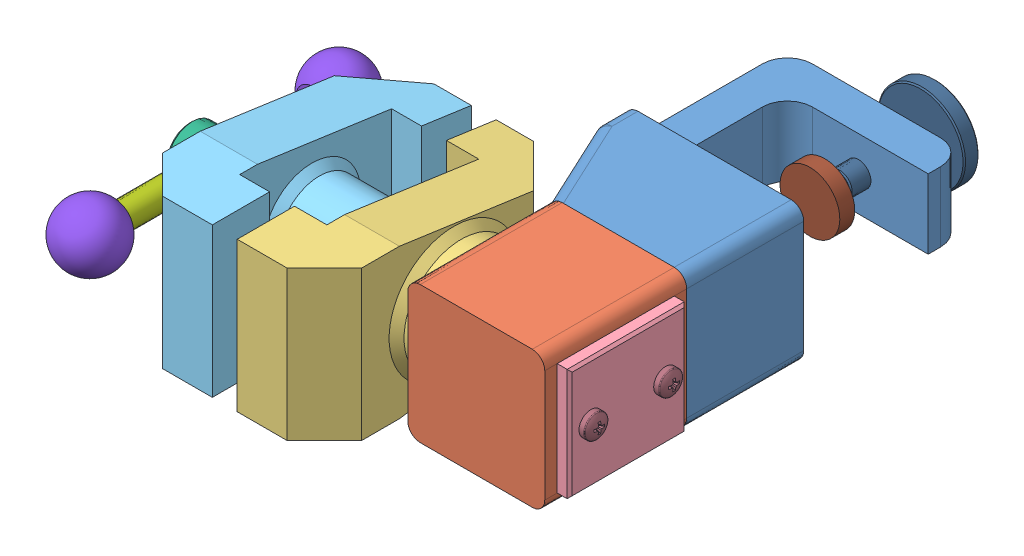
SolidWorks assembly Satu, configuration Default. Lengths in mm.
Overall size (187.08 60 219).
19 component instances, 14 part files, 49 mates.
Components (placement in the parent):
- alap-1: alap [Default] at origin size (71.55 55 112)
- Középsõrész-1: Középsõrész [Default] at (12.5535 55 114.3403) x (0 -1 0) z (0 0 1) size (55 55 92)
- pofa2-1: pofa2 [Default] at (2.5535 57.5 192.4977) x (0 -1 0) z (0 0 -1) size (60 99.5 104)
- vége_1-1: vége_1 [Default] at (72.5535 27.5 140.4977) x (0 1 0) z (0 0 -1) size (45 90 47)
- pofa1-1: pofa1 [Default] at (-77.4465 -2.5 192.4977) x (0 1 0) z (0 0 -1) size (60 113 104)
- tengely-1: tengely [Default] at (-103.4465 27.5 140.4977) x (0 1 0) z (0 0 1) size (20 136.13 20)
- kar_1-2: kar_1 [Default] at (-93.5765 27.5 192.9977) x (1 0 0) z (0 1 0) size (10 95 10)
- Gömb fej-1: Gömb fej [Default] at (-93.5765 27.5 90.4977) x (0.992385 -0.123178 0) z (0 0 1) size (25 25 23)
- Gömb fej-2: Gömb fej [Default] at (-93.5765 27.5 190.4977) x (-0.834442 -0.551096 0) z (0 0 -1) size (25 25 23)
- tengely_vége-1: tengely_vége [Default] at (-80.4465 27.5 140.4977) x (0 0 -1) z (0 -1 0) size (45 3 43.53)
- Szorito-1: Szorito [Default] at (39.55 27.5139 -16) x (-0.923728 -0.383049 0) z (-0.383049 0.923728 0) size (35 49.71 35)
- Szorito 2-2: Szorito 2 [Default] at (39.55 27.5139 28.5) x (-0.349136 -0.937072 0) z (-0.937072 0.349136 0) size (24 6 24)
- stift-1: stift [Default] at (-8.688 2.0341 140.5874) x (-0.914907 0 -0.403665) z (0 1 0) size (10 10 11)
- pan head cross recess screw_din-6: pan head cross recess screw_din [DIN EN ISO 7045 - M5 x 16 - Z - 16C] at (76.2535 27.5 155.4977) x (-1 0 0) z (0 1 0) size (19.63 9.5 9.5)
- pan head cross recess screw_din-7: pan head cross recess screw_din [DIN EN ISO 7045 - M5 x 16 - Z - 16C] at (-84.1465 27.5 123.9977) size (19.63 9.5 9.5)
- pan head cross recess screw_din-8: pan head cross recess screw_din [DIN EN ISO 7045 - M5 x 16 - Z - 16C] at (76.2535 27.5 125.4977) x (-1 0 0) z (0 0 -1) size (19.63 9.5 9.5)
- pan head cross recess screw_din-9: pan head cross recess screw_din [DIN EN ISO 7045 - M5 x 16 - Z - 16C] at (-84.1465 27.5 156.9977) x (1 0 0) z (0 -1 0) size (19.63 9.5 9.5)
- socket set screw dog point_din-2: socket set screw dog point_din [DIN 915 - M8 x 10-C] at (40.05 -0.5 88.5) x (0 1 0) z (-0.866025 0 0.5) size (10 8 8)
- socket set screw dog point_din-3: socket set screw dog point_din [DIN 915 - M8 x 10-C] at (40.0535 -1.7481 140.4977) x (0 1 0) z (0.866025 0 -0.5) size (10 8 8)
Mates (geometry in assembly coordinates):
- Concentric1: concentric aligned: cylinder of alap-1 through (40.0535 27.5 67) axis (0 0 1) radius 20; cylinder of Középsõrész-1 through (40.0535 27.5 79.3403) axis (0 0 1) radius 20
- Coincident1: coincident anti-aligned: plane of alap-1 through (65 55 112) normal (0 0 1); plane of Középsõrész-1 through (62.5535 5 112) normal (0 0 -1)
- Concentric2: concentric aligned: cylinder of Középsõrész-1 through (-184.3013 27.5 140.4977) axis (1 0 0) radius 21.5; cylinder of pofa2-1 through (40.537 27.5 140.4977) axis (1 0 0) radius 21.5
- Parallel1: parallel aligned: plane of Középsõrész-1 through (62.5535 5 168.9953) normal (0 0 1); plane of pofa2-1 through (-32.4465 27.5 192.4977) normal (0 0 1)
- Coincident4: coincident aligned: plane of alap-1 through (60 55 70) normal (0 1 0); plane of Középsõrész-1 through (62.5535 55 169.3403) normal (0 1 0)
- Concentric3: concentric aligned: cylinder of pofa2-1 through (46.7781 27.5 140.4977) axis (1 0 0) radius 11.5; cylinder of vége_1-1 through (-17.4465 27.5 140.4977) axis (1 0 0) radius 10.5
- Concentric5: concentric anti-aligned: cylinder of pofa2-1 through (-77.4465 27.5 140.4977) axis (1 0 0) radius 16.5; cylinder of pofa1-1 through (35.5535 27.5 140.4977) axis (-1 0 0) radius 16.5
- Coincident6: coincident aligned: plane of pofa2-1 through (-32.4465 27.5 192.4977) normal (0 0 1); plane of pofa1-1 through (-42.4465 27.5 192.4977) normal (0 0 1)
- Parallel2: parallel aligned: plane of Középsõrész-1 through (62.5535 55 169.3403) normal (0 1 0); plane of vége_1-1 through (-5.0688 50 168.9977) normal (0 1 0)
- Coincident10: coincident anti-aligned: plane of Középsõrész-1 through (67.5535 5 169.3403) normal (1 0 0); plane of vége_1-1 through (67.5535 27.5 140.4977) normal (-1 0 0)
- Concentric6: concentric aligned: cylinder of vége_1-1 through (-17.4465 27.5 140.4977) axis (-1 0 0) radius 4.6; cylinder of tengely-1 through (32.5535 27.5 140.4977) axis (-1 0 0) radius 5
- Coincident12: coincident aligned: plane of pofa1-1 through (-77.4465 -2.5 192.4977) normal (-1 0 0); plane of tengely-1 through (-77.4465 27.5 140.4977) normal (-1 0 0)
- Perpendicular1: perpendicular: line of pofa1-1 through (-62.4465 57.5 192.4977) axis (0 -1 0); cylinder of kar_1-2 through (-93.5765 27.5 92.9977) axis (0 0 1) radius 5
- Distance2: distance = 10 mm anti-aligned: plane of pofa1-1 through (-42.4465 -2.5 192.4977) normal (1 0 0); plane of pofa2-1 through (-32.4465 57.5 192.4977) normal (-1 0 0)
- Distance3: distance = 47.5 mm aligned: plane of kar_1-2 through (-93.5765 27.5 187.9977) normal (0 0 1); plane of tengely-1 through (-103.4465 27.5 140.4977) normal (0 0 1)
- Coincident20: coincident aligned: plane of tengely-1 through (-103.4465 27.5 140.4977) normal (0 1 0); plane of kar_1-2 through (-93.5765 27.5 192.9977) normal (0 1 0)
- Distance4: distance = 10 mm anti-aligned: plane of tengely-1 through (-103.5765 27.5 140.4977) normal (-1 0 0); plane of kar_1-2 through (-93.5765 27.5 192.9977) normal (1 0 0)
- Concentric9: concentric aligned: cylinder of kar_1-2 through (-93.5765 27.5 92.9977) axis (0 0 1) radius 5; cylinder of Gömb fej-1 through (-93.5765 27.5 100.9977) axis (0 0 1) radius 4.6
- Distance5: distance = 8 mm anti-aligned: plane of Gömb fej-1 through (-93.5765 27.5 100.9977) normal (0 0 1); plane of kar_1-2 through (-93.5765 27.5 92.9977) normal (0 0 -1)
- Concentric10: concentric anti-aligned: cylinder of kar_1-2 through (-93.5765 27.5 92.9977) axis (0 0 1) radius 5; cylinder of Gömb fej-2 through (-93.5765 27.5 179.9977) axis (0 0 -1) radius 4.6
- Distance6: distance = 8 mm anti-aligned: plane of Gömb fej-2 through (-93.5765 27.5 179.9977) normal (0 0 -1); plane of kar_1-2 through (-93.5765 27.5 187.9977) normal (0 0 1)
- Coincident24: coincident anti-aligned: plane of pofa1-1 through (-77.4465 -2.5 192.4977) normal (-1 0 0); plane of tengely_vége-1 through (-77.4465 27.5 140.4977) normal (1 0 0)
- Concentric11: concentric aligned: cylinder of tengely-1 through (-80.4465 27.5 140.4977) axis (-1 0 0) radius 10; cylinder of tengely_vége-1 through (-77.4465 27.5 140.4977) axis (-1 0 0) radius 22.5
- Parallel10: parallel anti-aligned: plane of pofa1-1 through (-42.4465 27.5 192.4977) normal (0 0 1); plane of tengely_vége-1 through (-77.4465 27.5 148.4977) normal (0 0 -1)
- Coincident27: coincident anti-aligned: plane of Középsõrész-1 through (12.5535 50 169.3403) normal (-1 0 0); plane of pofa2-1 through (12.5535 27.5 140.4977) normal (1 0 0)
- Concentric13: concentric aligned: cylinder of Szorito-1 through (39.55 27.5139 -16) axis (0 0 -1) radius 5; cylinder of alap-1 through (39.55 27.5139 0) axis (0 0 -1) radius 4.25
- Distance7: distance = 10 mm anti-aligned: plane of Szorito-1 through (39.55 27.5139 -10) normal (0 0 1); plane of alap-1 through (3 55 0) normal (0 0 -1)
- Concentric15: concentric aligned: cylinder of Szorito-1 through (39.55 27.5139 -16) axis (0 0 -1) radius 5; cylinder of Szorito 2-2 through (39.55 27.5139 33.7) axis (0 0 -1) radius 12
- Distance8: distance = 19.5 mm aligned: plane of Szorito 2-2 through (43.7396 38.7588 34.5) normal (0 0 1); plane of alap-1 through (48 55 15) normal (0 0 1)
- Concentric281: concentric aligned: cylinder of pofa2-1 through (-8.688 57.501 140.5874) axis (0 -1 0) radius 5; cylinder of stift-1 through (-8.688 13.0341 140.5874) axis (0 -1 0) radius 5
- Coincident411: coincident anti-aligned: plane of pofa1-1 through (13.5535 13.0341 140.4977) normal (0 -1 0); plane of stift-1 through (-8.688 13.0341 140.5874) normal (0 1 0)
- Concentric2821: concentric aligned: cylinder of pofa2-1 through (67.0581 27.5 155.4977) axis (1 0 0) radius 2.1; cylinder of pan head cross recess screw_din-6 through (101.6535 27.5 155.4977) axis (1 0 0) radius 2.5
- Coincident4121: coincident anti-aligned: plane of vége_1-1 through (72.5535 27.5 140.4977) normal (1 0 0); plane of pan head cross recess screw_din-6 through (72.5535 27.5 157.9977) normal (-1 0 0)
- Parallel111: parallel aligned: plane of vége_1-1 through (-5.0688 5 168.9977) normal (0 -1 0); plane of pan head cross recess screw_din-6 through (76.2535 28.015 153.1477) normal (0 -1 0)
- Concentric2831: concentric aligned: cylinder of vége_1-1 through (-17.4475 27.5 125.4977) axis (1 0 0) radius 2.6; cylinder of pan head cross recess screw_din-8 through (101.6535 27.5 125.4977) axis (1 0 0) radius 2.5
- Coincident4141: coincident anti-aligned: plane of vége_1-1 through (72.5535 27.5 140.4977) normal (1 0 0); plane of pan head cross recess screw_din-8 through (72.5535 30 125.4977) normal (-1 0 0)
- Parallel121: parallel aligned: plane of vége_1-1 through (-5.0688 5 168.9977) normal (0 -1 0); plane of pan head cross recess screw_din-8 through (76.2535 28.015 123.1477) normal (0 -1 0)
- Concentric2841: concentric aligned: cylinder of tengely_vége-1 through (-20.4465 27.5 156.9977) axis (-1 0 0) radius 2.6; cylinder of pan head cross recess screw_din-9 through (-109.5465 27.5 156.9977) axis (-1 0 0) radius 2.5
- Coincident4161: coincident anti-aligned: plane of tengely_vége-1 through (-80.4465 27.5 140.4977) normal (-1 0 0); plane of pan head cross recess screw_din-9 through (-80.4465 27.5 159.4977) normal (1 0 0)
- Parallel131: parallel aligned: plane of Középsõrész-1 through (17.5535 0 169.3403) normal (0 -1 0); plane of pan head cross recess screw_din-9 through (-84.1465 28.015 159.3477) normal (0 -1 0)
- Concentric2851: concentric aligned: cylinder of tengely_vége-1 through (-20.4465 27.5 123.9977) axis (-1 0 0) radius 2.6; cylinder of pan head cross recess screw_din-7 through (-109.5465 27.5 123.9977) axis (-1 0 0) radius 2.5
- Coincident4181: coincident anti-aligned: plane of tengely_vége-1 through (-80.4465 27.5 140.4977) normal (-1 0 0); plane of pan head cross recess screw_din-7 through (-80.4465 30 123.9977) normal (1 0 0)
- Parallel141: parallel aligned: plane of Középsõrész-1 through (17.5535 0 169.3403) normal (0 -1 0); plane of pan head cross recess screw_din-7 through (-84.1465 28.015 126.3477) normal (0 -1 0)
- Concentric2871: concentric aligned: cylinder of alap-1 through (40.05 0 88.5) axis (0 -1 0) radius 3.4; cylinder of socket set screw dog point_din-2 through (40.05 -13.2 88.5) axis (0 -1 0) radius 4
- Concentric2881: concentric aligned: cylinder of Középsõrész-1 through (40.0535 0 140.4977) axis (0 -1 0) radius 3.4; cylinder of socket set screw dog point_din-3 through (40.0535 -14.4481 140.4977) axis (0 -1 0) radius 4
- Tangent11: tangent anti-aligned: cylinder of Középsõrész-1 through (40.0535 27.5 74.3403) axis (0 0 1) radius 18; plane of socket set screw dog point_din-2 through (38.675 9.5 86.1184) normal (0 1 0)
- Tangent21: tangent anti-aligned: plane of socket set screw dog point_din-3 through (41.4285 8.2519 142.8792) normal (0 1 0); cylinder of pofa2-1 through (34.8151 27.5 140.4977) axis (1 0 0) radius 19.2481
- Parallel15: parallel aligned: plane of vége_1-1 through (72.5535 27.5 140.4977) normal (1 0 0); plane of socket set screw dog point_din-3 through (38.0535 1.2519 139.343) normal (1 0 0)
- Parallel16: parallel aligned: plane of vége_1-1 through (72.5535 27.5 140.4977) normal (1 0 0); plane of socket set screw dog point_din-2 through (38.05 2.5 87.3453) normal (1 0 0)
